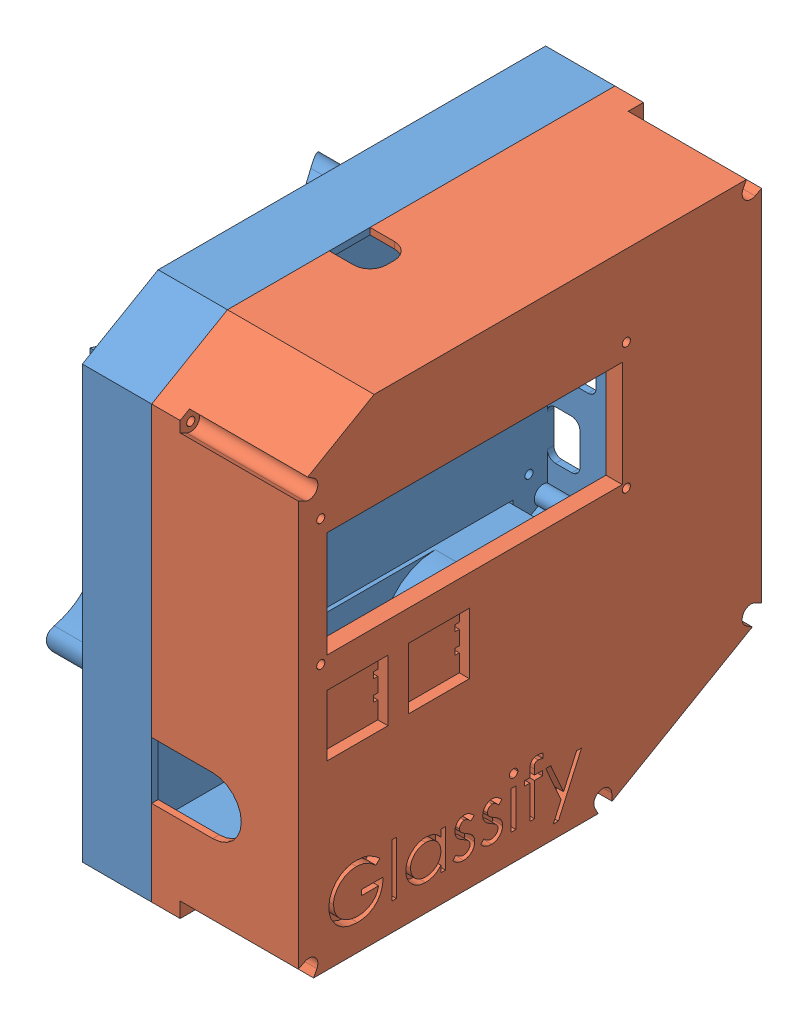
SolidWorks assembly ElectronicsAssembly, configuration Default. Lengths in mm.
Overall size (84.15 116.6 143.23).
3 component instances, 3 part files, 12 mates.
Components (placement in the parent):
- 120mmPipe^ElectronicsAssembly-1: 120mmPipe^ElectronicsAssembly [Default] x (1 0 0) z (0 1 0) size (124 124 350) (hidden, virtual)
- ElectronicsHousing-1: ElectronicsHousing [Default] at (62 0 0) x (0 0 -1) z (1 0 0) size (143.23 116.6 48.15)
- ElectronicsHousingCover-1: ElectronicsHousingCover [Default] at (96 0 0) x (0 0 -1) z (1 0 0) size (113.7 116.6 36)
Mates (geometry in assembly coordinates):
- InPlace1: in place: plane of 120mmPipe^ElectronicsAssembly-1 through (0 0 0) normal (0 1 0); moOrthogonalPlaneRef_w of 120mmPipe^ElectronicsAssembly-1 through (0 0 0) normal (0 0 -1); plane of 120mmPipe^ElectronicsAssembly-1 through (0 0 0) normal (1 0 0); unknown of 120mmPipe^ElectronicsAssembly-1
- Coincident1: coincident: plane of 120mmPipe^ElectronicsAssembly-1; plane of assembly
- Coincident2: coincident: plane of 120mmPipe^ElectronicsAssembly-1 through (0 0 0) normal (0 0 -1); moOrthogonalPlaneRef_w of assembly
- Coincident3: coincident: plane of 120mmPipe^ElectronicsAssembly-1 through (0 0 0) normal (1 0 0); moOrthogonalPlaneRef_w of assembly
- InPlace2: in place: plane of ElectronicsHousing-1 through (62 0 0) normal (1 0 0); plane of ElectronicsHousing-1 through (62 0 0) normal (0 1 0); plane of ElectronicsHousing-1 through (62 0 0) normal (0 0 -1); unknown of ElectronicsHousing-1
- Coincident4: coincident: plane of ElectronicsHousing-1; plane of assembly
- Coincident5: coincident: plane of ElectronicsHousing-1 through (62 0 0) normal (0 1 0); moOrthogonalPlaneRef_w of assembly
- Coincident6: coincident: plane of ElectronicsHousing-1 through (62 0 0) normal (0 0 -1); moOrthogonalPlaneRef_w of assembly
- InPlace3: in place: plane of ElectronicsHousing-1 through (88 0 0) normal (1 0 0); plane of ? through (88 0 0) normal (1 0 0); plane of ElectronicsHousing-1 through (88 0 0) normal (1 0 0); plane of ? through (88 0 0) normal (0 1 0); plane of ElectronicsHousing-1 through (88 0 0) normal (1 0 0); plane of ? through (88 0 0) normal (0 0 -1); plane of ElectronicsHousing-1 through (96 0 0) normal (1 0 0); unknown of ElectronicsHousingCover-1
- Coincident1: coincident: plane of ElectronicsHousing-1 through (96 0 0) normal (1 0 0); plane of ElectronicsHousingCover-1 through (96 0 0) normal (1 0 0)
- Coincident2: coincident: moOrthogonalPlaneRef_w of ElectronicsHousing-1 through (96 0 0) normal (0 1 0); plane of ElectronicsHousingCover-1 through (96 0 0) normal (0 1 0)
- Coincident3: coincident: moOrthogonalPlaneRef_w of ElectronicsHousing-1 through (96 0 0) normal (0 0 1); plane of ElectronicsHousingCover-1 through (96 0 0) normal (0 0 -1)
